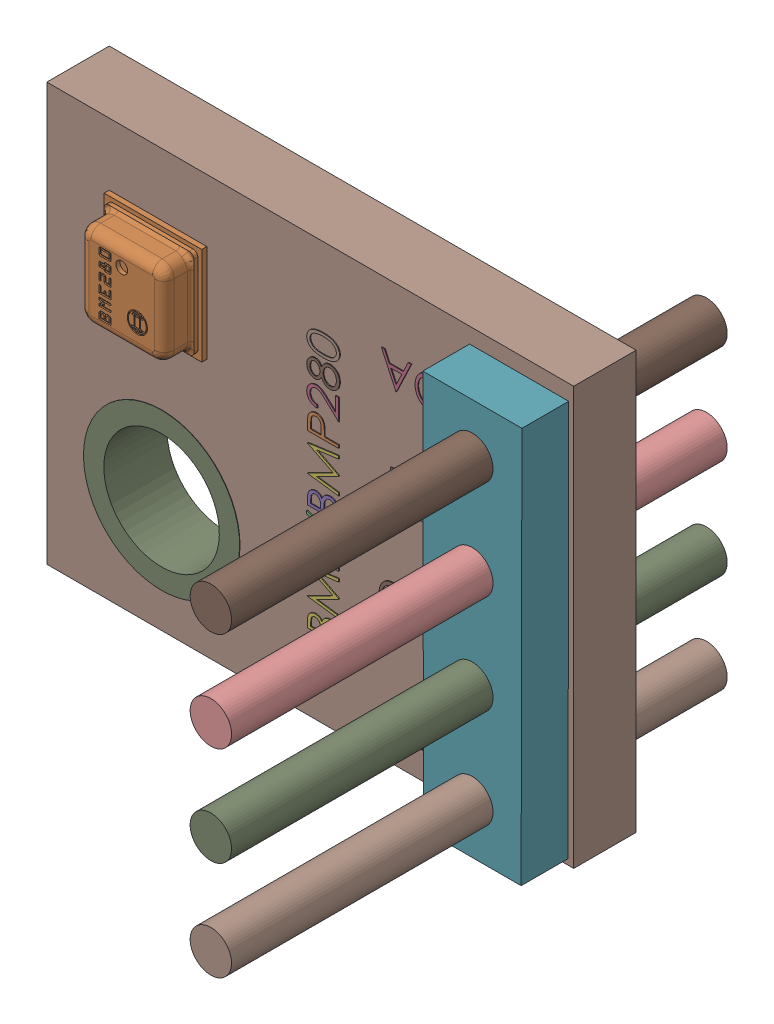
SolidWorks assembly BMP, configuration Default. Lengths in mm.
Overall size (13.55 10.7 12.7).
11 component instances, 3 part files, 0 mates.
Components (placement in the parent):
- GY-BME280-1: GY-BME280 [Default] at (155.5751 97.6629 0) x (0 1 0) z (0 0 1) size (10.7 13.55 3.64)
- 1185083472-1: 1185083472 [Default] at (154.178 97.536 0) size (2.54 10.16 2.8)
  - Extruded-1: Extruded [Default] at origin size (2.54 10.16 2.8)
- 1185083552-1: 1185083552 [Default] at (154.1779 93.7261 -3.2) x (0 1 0) z (0 0 1) size (1.06 1.06 12.7)
  - Cylinder-1: Cylinder [Default] at origin size (1.06 1.06 12.7)
- 1185083552-2: 1185083552 [Default] at (154.1779 96.2661 -3.2) x (0 1 0) z (0 0 1) size (1.06 1.06 12.7)
  - Cylinder-1: Cylinder [Default] at origin size (1.06 1.06 12.7)
- 1185083552-3: 1185083552 [Default] at (154.1779 98.8061 -3.2) x (0 1 0) z (0 0 1) size (1.06 1.06 12.7)
  - Cylinder-1: Cylinder [Default] at origin size (1.06 1.06 12.7)
- 1185083552-4: 1185083552 [Default] at (154.1779 101.3461 -3.2) x (0 1 0) z (0 0 1) size (1.06 1.06 12.7)
  - Cylinder-1: Cylinder [Default] at origin size (1.06 1.06 12.7)
